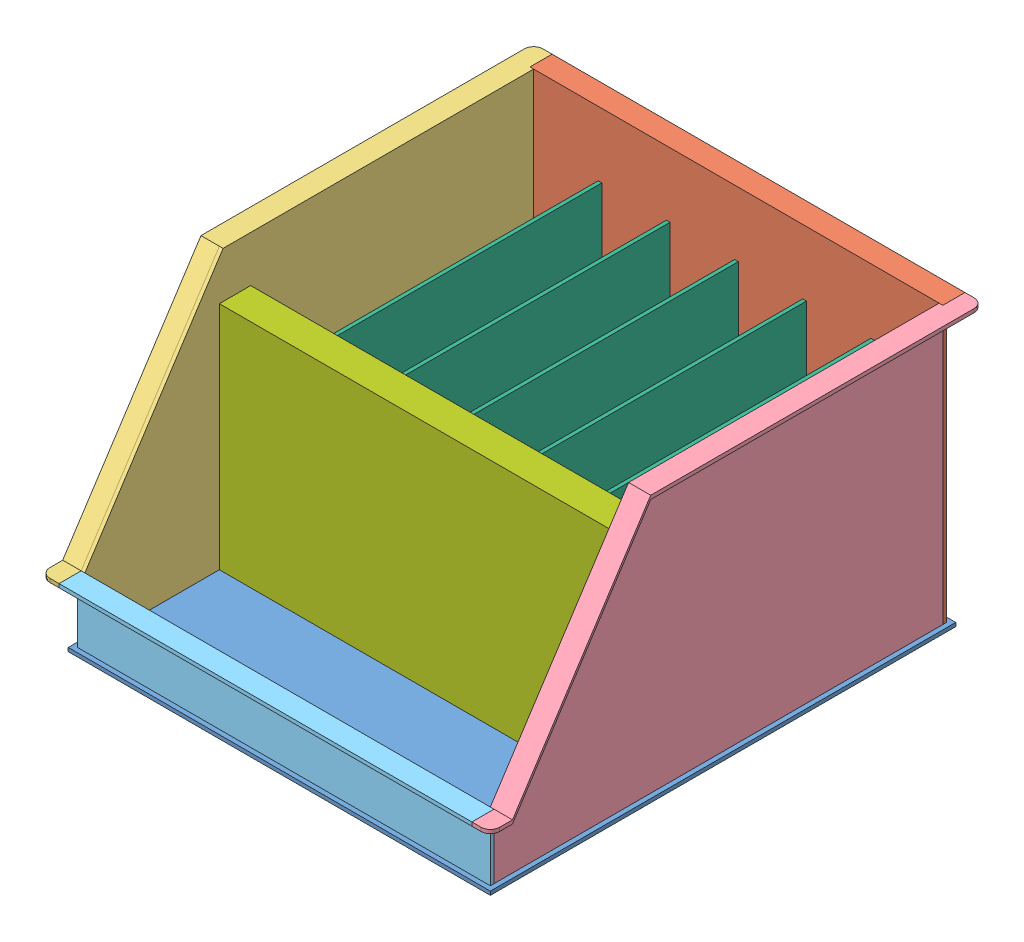
SolidWorks assembly BatteryBox, configuration Default. Lengths in mm.
Overall size (488 304 535).
11 component instances, 7 part files, 24 mates.
Components (placement in the parent):
- box_base-1: box_base [Default] at (-41.9141 184.8935 556.0522) size (458 4 505)
- box_back-1: box_back [Default] at (411.0859 188.8935 56.0522) x (-1 0 0) z (0 0 -1) size (448 300 24)
- box_side-1: box_side [Default] at (-32.9141 188.8935 60.0522) x (0 0 1) z (-1 0 0) size (535 300 24)
- box_sidemirrored-2: box_sidemirrored [Default] at (411.0859 188.8935 60.0522) x (0 0 1) z (-1 0 0) size (535 300 24)
- box_front-1: box_front [Default] at (187.0859 188.8935 547.0522) x (-1 0 0) z (0 0 -1) size (448 70 24)
- box_inner-1: box_inner [Default] at (333.0859 188.8935 397.0522) x (0 0 -1) z (1 0 0) size (337 230 4)
- box_inner-2: box_inner [Default] at (259.0859 188.8935 397.0522) x (0 0 -1) z (1 0 0) size (337 230 4)
- box_inner-3: box_inner [Default] at (185.0859 188.8935 397.0522) x (0 0 -1) z (1 0 0) size (337 230 4)
- box_inner-4: box_inner [Default] at (111.0859 188.8935 397.0522) x (0 0 -1) z (1 0 0) size (337 230 4)
- box_inner-5: box_inner [Default] at (37.0859 188.8935 397.0522) x (0 0 -1) z (1 0 0) size (337 230 4)
- box_frontdivider-1: box_frontdivider [Default] at (407.0859 188.8935 401.0522) x (-1 0 0) z (0 0 -1) size (440 250 34)
Mates (geometry in assembly coordinates):
- Coincident3: coincident aligned: line of box_side-1 through (-36.9141 188.8935 547.0522) axis (0 1 0); line of box_front-1 through (-36.9141 188.8935 547.0522) axis (0 1 0)
- Coincident4: coincident anti-aligned: line of box_sidemirrored-2 through (411.0859 188.8935 547.0522) axis (0 1 0); line of box_front-1 through (411.0859 258.8935 547.0522) axis (0 -1 0)
- Coincident6: coincident aligned: line of box_back-1 through (411.0859 488.8935 60.0522) axis (0 -1 0); line of box_sidemirrored-2 through (411.0859 484.8935 60.0522) axis (0 -1 0)
- Coincident7: coincident anti-aligned: line of box_back-1 through (-36.9141 188.8935 60.0522) axis (0 1 0); line of box_side-1 through (-36.9141 484.8935 60.0522) axis (0 -1 0)
- Coincident9: coincident anti-aligned: line of box_back-1 through (411.0859 188.8935 60.0522) axis (-1 0 0); line of box_sidemirrored-2 through (407.0859 188.8935 60.0522) axis (1 0 0)
- Coincident10: coincident anti-aligned: line of box_side-1 through (-36.9141 188.8935 547.0522) axis (1 0 0); line of box_front-1 through (411.0859 188.8935 547.0522) axis (-1 0 0)
- Coincident23: coincident anti-aligned: line of box_sidemirrored-2 through (411.0859 188.8935 547.0522) axis (0 1 0); line of box_front-1 through (411.0859 258.8935 547.0522) axis (0 -1 0)
- Coincident24: coincident anti-aligned: plane of box_sidemirrored-2 through (407.0859 258.8935 547.0522) normal (0 0 1); plane of box_front-1 through (187.0859 188.8935 547.0522) normal (0 0 -1)
- Coincident25: coincident anti-aligned: line of box_sidemirrored-2 through (407.0859 188.8935 547.0522) axis (1 0 0); line of box_front-1 through (411.0859 188.8935 547.0522) axis (-1 0 0)
- Coincident26: coincident: point of box_base-1; point of box_back-1
- Coincident27: coincident: point of box_base-1; point of box_back-1
- Coincident29: coincident: point of box_base-1; point of box_front-1
- Coincident30: coincident anti-aligned: line of box_inner-5 through (41.0859 188.8935 397.0522) axis (0 0 -1); line of box_base-1 through (41.0859 188.8935 56.0522) axis (0 0 1)
- Coincident31: coincident anti-aligned: line of box_base-1 through (-36.9141 188.8935 397.0522) axis (1 0 0); line of box_inner-5 through (41.0859 188.8935 397.0522) axis (-1 0 0)
- Coincident32: coincident anti-aligned: line of box_inner-4 through (115.0859 188.8935 397.0522) axis (0 0 -1); line of box_base-1 through (115.0859 188.8935 56.0522) axis (0 0 1)
- Coincident33: coincident anti-aligned: line of box_base-1 through (-36.9141 188.8935 397.0522) axis (1 0 0); line of box_inner-4 through (115.0859 188.8935 397.0522) axis (-1 0 0)
- Coincident34: coincident anti-aligned: line of box_base-1 through (-36.9141 188.8935 397.0522) axis (1 0 0); line of box_inner-3 through (189.0859 188.8935 397.0522) axis (-1 0 0)
- Coincident35: coincident anti-aligned: line of box_base-1 through (189.0859 188.8935 56.0522) axis (0 0 1); line of box_inner-3 through (189.0859 188.8935 397.0522) axis (0 0 -1)
- Coincident36: coincident anti-aligned: line of box_base-1 through (-36.9141 188.8935 397.0522) axis (1 0 0); line of box_inner-2 through (263.0859 188.8935 397.0522) axis (-1 0 0)
- Coincident37: coincident anti-aligned: line of box_base-1 through (263.0859 188.8935 56.0522) axis (0 0 1); line of box_inner-2 through (263.0859 188.8935 397.0522) axis (0 0 -1)
- Coincident38: coincident anti-aligned: line of box_base-1 through (-36.9141 188.8935 397.0522) axis (1 0 0); line of box_inner-1 through (337.0859 188.8935 397.0522) axis (-1 0 0)
- Coincident39: coincident anti-aligned: line of box_base-1 through (337.0859 188.8935 56.0522) axis (0 0 1); line of box_inner-1 through (337.0859 188.8935 397.0522) axis (0 0 -1)
- Coincident40: coincident anti-aligned: line of box_base-1 through (-36.9141 188.8935 401.0522) axis (1 0 0); line of box_frontdivider-1 through (407.0859 188.8935 401.0522) axis (-1 0 0)
- Coincident41: coincident aligned: line of box_sidemirrored-2 through (407.0859 188.8935 60.0522) axis (0 0 1); line of box_frontdivider-1 through (407.0859 188.8935 397.0522) axis (0 0 1)
